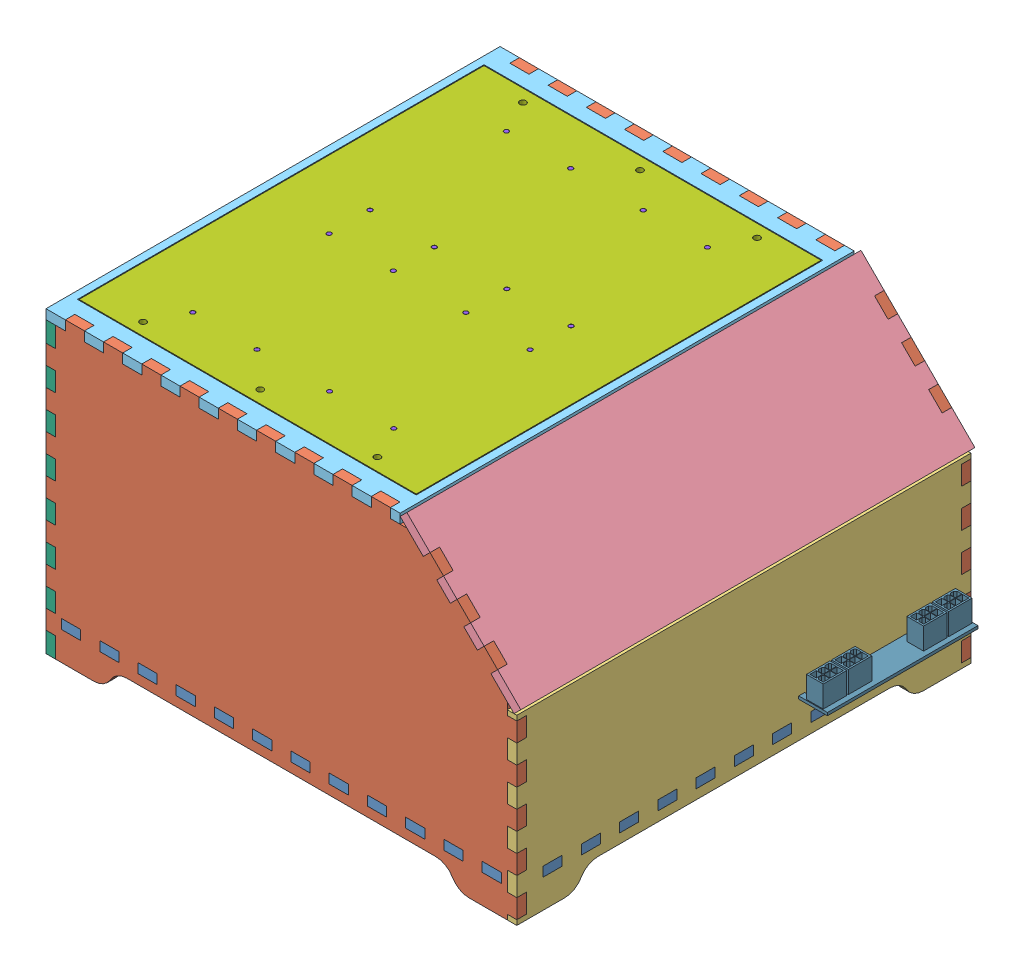
SolidWorks assembly REV 3 Full Machine, configuration Default. Lengths in mm.
Overall size (302.36 180.94 271.43).
34 component instances, 14 part files, 36 mates.
Components (placement in the parent):
- Bottom-1: Bottom [Default] at (-719.689 5.715 -158.5753) x (1 0 0) z (0 -1 0) size (281.43 271.43 5.71)
- Side-1: Side [Default] at (-151.1127 -40.0054 -135.7151) size (281.43 178.58 5.71)
- Side-2: Side [Default] at (-151.1148 -40.0054 130.0001) size (281.43 178.58 5.71)
- Front-1: Front [Default] at (140.7172 -880.4091 158.5753) x (0 1 0) z (-1 0 0) size (108.82 271.43 5.71)
- Front Panel-1: Front Panel [Default] at (-614.3853 853.1825 -158.5753) x (0.707107 -0.707107 0) z (-0.707107 -0.707107 0) size (96.28 271.43 5.71)
- Top-1: Top [Default] at (1145.0391 161.4301 158.5753) x (-1 0 0) z (0 -1 0) size (211.67 271.43 5.71)
- Back-1: Back [Default] at (-140.7152 1444.3252 158.5753) x (0 -1 0) z (1 0 0) size (172.86 271.43 5.71)
- Peltier Assembly 2.0-1: Peltier Assembly 2.0 [Default] at (-34.8782 161.4301 0) x (-1 0 0) z (0 0 1) size (201.5 67.45 242)
  - Cold plate 2.0-1: Cold plate 2.0 [Default] at (-100.75 0 -221.75) x (0 0 1) z (0 1 0) size (242 201.5 3)
  - 91772A162_Passivated 18-8 Stainless Steel Pan Head Phillips Screw-1: 91772A162_Passivated 18-8 Stainless Steel Pan Head Phillips Screw [91772A162] at (21.675 0 93.75) x (0.999996 0 0.002747) z (0 1 0) size (6.86 6.86 16.79)
  - 91772A162_Passivated 18-8 Stainless Steel Pan Head Phillips Screw-2: 91772A162_Passivated 18-8 Stainless Steel Pan Head Phillips Screw [91772A162] at (-21.675 0 93.75) x (0.999996 0 0.002747) z (0 1 0) size (6.86 6.86 16.79)
  - 91772A162_Passivated 18-8 Stainless Steel Pan Head Phillips Screw-3: 91772A162_Passivated 18-8 Stainless Steel Pan Head Phillips Screw [91772A162] at (-60.075 0 93.75) x (0.999996 0 0.002747) z (0 1 0) size (6.86 6.86 16.79)
  - 91772A162_Passivated 18-8 Stainless Steel Pan Head Phillips Screw-4: 91772A162_Passivated 18-8 Stainless Steel Pan Head Phillips Screw [91772A162] at (60.075 0 93.75) x (0.999996 0 0.002747) z (0 1 0) size (6.86 6.86 16.79)
  - 91772A162_Passivated 18-8 Stainless Steel Pan Head Phillips Screw-5: 91772A162_Passivated 18-8 Stainless Steel Pan Head Phillips Screw [91772A162] at (21.675 0 12.25) x (0.999996 0 0.002747) z (0 1 0) size (6.86 6.86 16.79)
  - 91772A162_Passivated 18-8 Stainless Steel Pan Head Phillips Screw-6: 91772A162_Passivated 18-8 Stainless Steel Pan Head Phillips Screw [91772A162] at (-21.675 0 12.25) x (0.999996 0 0.002747) z (0 1 0) size (6.86 6.86 16.79)
  - 91772A162_Passivated 18-8 Stainless Steel Pan Head Phillips Screw-7: 91772A162_Passivated 18-8 Stainless Steel Pan Head Phillips Screw [91772A162] at (-60.075 0 12.25) x (0.999996 0 0.002747) z (0 1 0) size (6.86 6.86 16.79)
  - 91772A162_Passivated 18-8 Stainless Steel Pan Head Phillips Screw-8: 91772A162_Passivated 18-8 Stainless Steel Pan Head Phillips Screw [91772A162] at (21.675 0 -12.25) x (0.999996 0 0.002747) z (0 1 0) size (6.86 6.86 16.79)
  - 91772A162_Passivated 18-8 Stainless Steel Pan Head Phillips Screw-9: 91772A162_Passivated 18-8 Stainless Steel Pan Head Phillips Screw [91772A162] at (60.075 0 12.25) x (0.999996 0 0.002747) z (0 1 0) size (6.86 6.86 16.79)
  - 91772A162_Passivated 18-8 Stainless Steel Pan Head Phillips Screw-10: 91772A162_Passivated 18-8 Stainless Steel Pan Head Phillips Screw [91772A162] at (-21.675 0 -12.25) x (0.946183 0 -0.323632) z (0 1 0) size (6.86 6.86 16.79)
  - 91772A162_Passivated 18-8 Stainless Steel Pan Head Phillips Screw-11: 91772A162_Passivated 18-8 Stainless Steel Pan Head Phillips Screw [91772A162] at (60.075 0 -12.25) x (0.999996 0 0.002747) z (0 1 0) size (6.86 6.86 16.79)
  - 91772A162_Passivated 18-8 Stainless Steel Pan Head Phillips Screw-12: 91772A162_Passivated 18-8 Stainless Steel Pan Head Phillips Screw [91772A162] at (-60.075 0 -12.25) x (0.968243 0 -0.250012) z (0 1 0) size (6.86 6.86 16.79)
  - 91772A162_Passivated 18-8 Stainless Steel Pan Head Phillips Screw-13: 91772A162_Passivated 18-8 Stainless Steel Pan Head Phillips Screw [91772A162] at (60.075 0 -93.75) x (0.999996 0 0.002747) z (0 1 0) size (6.86 6.86 16.79)
  - 91772A162_Passivated 18-8 Stainless Steel Pan Head Phillips Screw-14: 91772A162_Passivated 18-8 Stainless Steel Pan Head Phillips Screw [91772A162] at (21.675 0 -93.75) x (0.999996 0 0.002747) z (0 1 0) size (6.86 6.86 16.79)
  - 91772A162_Passivated 18-8 Stainless Steel Pan Head Phillips Screw-15: 91772A162_Passivated 18-8 Stainless Steel Pan Head Phillips Screw [91772A162] at (-21.675 0 -93.75) x (0.893935 0 0.448197) z (0 1 0) size (6.86 6.86 16.79)
  - 91772A162_Passivated 18-8 Stainless Steel Pan Head Phillips Screw-16: 91772A162_Passivated 18-8 Stainless Steel Pan Head Phillips Screw [91772A162] at (-60.075 0 -93.75) x (-0.993494 0 -0.113885) z (0 1 0) size (6.86 6.86 16.79)
  - Acrylic seperator-1: Acrylic seperator [Default] at (100.75 3 219) x (0 0 -1) z (0 1 0) size (240 200 3)
  - Heatsink 3.0-5: Heatsink 3.0 [Default] at (40.875 6 -53) size (78.2 61.32 89)
  - Heatsink 3.0-6: Heatsink 3.0 [Default] at (-40.875 6 -53) size (78.2 61.32 89)
  - Heatsink 3.0-7: Heatsink 3.0 [Default] at (40.875 6 53) size (78.2 61.32 89)
  - Heatsink 3.0-8: Heatsink 3.0 [Default] at (-40.875 6 53) size (78.2 61.32 89)
- Front Divider-1: Front Divider [Default] at (50.9968 5.715 129.9999) x (0 0 -1) z (0 -1 0) size (260 5.71 150)
- Lower divider-1: Lower divider [Default] at (50.9968 45.715 129.9999) x (0 0 -1) z (1 0 0) size (260 3.05 186)
- PSU-1: PSU [Default] at (-140.7152 11.43 -120.1408) x (0 0 1) z (-1 0 0) size (87 40 208.61)
- PSU adapter board-1: PSU adapter board [Default] at (111.8948 15.75 -77.7658) x (0 0 -1) z (1 0 0) size (90 17.46 103.75)
Mates (geometry in assembly coordinates):
- Symmetric1: symmetric aligned: plane of Bottom-1 through (-5.7154 0 135.7151) normal (0 0 1); plane of Bottom-1 through (-17.1425 0 -135.7151) normal (0 0 -1)
- Symmetric2: symmetric aligned: plane of Bottom-1 through (-140.7155 0 -17.1451) normal (-1 0 0); plane of Bottom-1 through (140.7155 0 -28.5751) normal (1 0 0)
- Coincident5: coincident anti-aligned: plane of Bottom-1 through (-719.689 0 -158.5753) normal (0 -1 0)
- Coincident6: coincident anti-aligned: plane of Bottom-1 through (-120.0155 0 -130.0001) normal (0 0 -1); plane of Side-1 through (-151.1127 -40.0054 -130.0001) normal (0 0 1)
- Coincident7: coincident anti-aligned: plane of Bottom-1 through (-719.689 0 -158.5753) normal (0 -1 0); plane of Side-1 through (-125.7277 0 -130.0001) normal (0 1 0)
- Coincident8: coincident anti-aligned: plane of Bottom-1 through (-131.4427 0 -130.0001) normal (-1 0 0); plane of Side-1 through (-131.4427 0 -130.0001) normal (1 0 0)
- Coincident9: coincident anti-aligned: plane of Bottom-1 through (120.0155 0 135.7151) normal (-1 0 0); plane of Side-2 through (120.0155 0 135.7151) normal (1 0 0)
- Coincident10: coincident anti-aligned: plane of Bottom-1 through (-719.689 0 -158.5753) normal (0 -1 0); plane of Side-2 through (125.7301 0 135.7151) normal (0 1 0)
- Coincident11: coincident aligned: plane of Bottom-1 through (108.5848 0 135.7151) normal (0 0 1); plane of Side-2 through (-151.1148 -40.0054 135.7151) normal (0 0 1)
- Coincident13: coincident anti-aligned: plane of Bottom-1 through (-135.0002 0 40.0049) normal (-1 0 0); plane of Back-1 through (-135.0002 1444.3252 158.5753) normal (1 0 0)
- Coincident14: coincident aligned: plane of Side-1 through (-106.3135 155.7151 -130.0001) normal (0 1 0); plane of Back-1 through (-135.0002 155.7151 -130.0001) normal (0 1 0)
- Coincident15: coincident aligned: plane of Side-2 through (-151.1148 -40.0054 135.7151) normal (0 0 1); plane of Back-1 through (-135.0002 155.7151 135.7151) normal (0 0 1)
- Coincident19: coincident anti-aligned: plane of Top-1 through (1145.0391 155.7151 158.5753) normal (0 -1 0); plane of Back-1 through (-135.0002 155.7151 -130.0001) normal (0 1 0)
- Coincident20: coincident aligned: plane of Top-1 through (-140.7152 155.7151 -130.0001) normal (-1 0 0); plane of Back-1 through (-140.7152 1444.3252 158.5753) normal (-1 0 0)
- Coincident21: coincident aligned: plane of Side-2 through (-151.1148 -40.0054 135.7151) normal (0 0 1); plane of Top-1 through (-106.3167 155.7151 135.7151) normal (0 0 1)
- Coincident22: coincident anti-aligned: plane of Side-1 through (135.0022 20.1189 -130.0001) normal (1 0 0); plane of Front-1 through (135.0022 -880.4091 158.5753) normal (-1 0 0)
- Coincident23: coincident aligned: plane of Side-1 through (112.1426 -17.1452 -130.0001) normal (0 -1 0); plane of Front-1 through (135.0022 -17.1452 -130.0001) normal (0 -1 0)
- Coincident24: coincident anti-aligned: plane of Side-1 through (-151.1127 -40.0054 -130.0001) normal (0 0 1); plane of Front-1 through (135.0022 -2.7416 -130.0001) normal (0 0 -1)
- Coincident25: coincident anti-aligned: plane of Side-2 through (84.7943 145.921 135.7151) normal (0.707107 0.707107 0); plane of Front Panel-1 through (-618.4264 849.1414 -158.5753) normal (-0.707107 -0.707107 0)
- Parallel1: parallel anti-aligned: line of Front-1 through (135.0022 91.6735 135.7151) axis (0 0 -1); line of Front Panel-1 through (139.0411 91.6738 -135.7151) axis (0 0 1)
- Coincident27: coincident aligned: plane of Side-2 through (-151.1148 -40.0054 135.7151) normal (0 0 1); plane of Front Panel-1 through (100.96 129.7549 135.7151) normal (0 0 1)
- Coincident28: coincident: point of Side-2; unknown of Front Panel-1
- Coincident29: coincident aligned: plane of Top-1 through (1145.0391 161.4301 158.5753) normal (0 1 0); plane of Peltier Assembly 2.0-1/Cold plate 2.0-1 through (-34.8782 161.4301 0) normal (0 1 0)
- Width1: width anti-aligned: plane of Peltier Assembly 2.0-1/Cold plate 2.0-1 through (65.8718 158.4301 -121) normal (1 0 0); plane of Top-1 through (-135.6282 158.4301 -121) normal (-1 0 0); plane of Peltier Assembly 2.0-1/Cold plate 2.0-1 through (-140.7152 155.7151 -130.0001) normal (-1 0 0); plane of Top-1 through (70.9587 155.7151 -130.0001) normal (1 0 0)
- Width2: width anti-aligned: plane of Peltier Assembly 2.0-1/Cold plate 2.0-1 through (-135.6282 158.4301 121) normal (0 0 1); plane of Side-1 through (-135.6282 158.4301 -121) normal (0 0 -1); plane of Peltier Assembly 2.0-1/Cold plate 2.0-1 through (-151.1127 -40.0054 -135.7151) normal (0 0 -1); plane of Side-2 through (-151.1148 -40.0054 135.7151) normal (0 0 1)
- Coincident30: coincident anti-aligned: plane of Side-1 through (-151.1127 -40.0054 -130.0001) normal (0 0 1); plane of Front Divider-1 through (56.7118 5.715 -130.0001) normal (0 0 -1)
- Coincident31: coincident anti-aligned: plane of Bottom-1 through (-719.689 5.715 -158.5753) normal (0 1 0); plane of Front Divider-1 through (56.7118 5.715 129.9999) normal (0 -1 0)
- Distance1: distance = 1 mm anti-aligned: plane of Front Divider-1 through (50.9968 5.715 129.9999) normal (-1 0 0); plane of Peltier Assembly 2.0-1/Heatsink 2.0-3 through (49.9968 122.5801 52.5) normal (1 0 0)
- Coincident33: coincident anti-aligned: plane of Front Divider-1 through (50.9968 5.715 129.9999) normal (-1 0 0); plane of Lower divider-1 through (50.9968 48.763 129.9999) normal (1 0 0)
- Coincident34: coincident aligned: plane of Front Divider-1 through (56.7118 5.715 129.9999) normal (0 0 1); plane of Lower divider-1 through (50.9968 48.763 129.9999) normal (0 0 1)
- Distance2: distance = 40 mm anti-aligned: plane of Bottom-1 through (-719.689 5.715 -158.5753) normal (0 1 0); plane of Lower divider-1 through (50.9968 45.715 129.9999) normal (0 -1 0)
- Coincident36: coincident aligned: plane of Back-1 through (-140.7152 1444.3252 158.5753) normal (-1 0 0); plane of PSU-1 through (-140.7152 6.215 -120.1408) normal (-1 0 0)
- Distance3: distance = 5.715 mm anti-aligned: plane of PSU-1 through (-106.7152 11.43 -120.1408) normal (0 -1 0); plane of Bottom-1 through (-719.689 5.715 -158.5753) normal (0 1 0)
- Coincident37: coincident anti-aligned: plane of PSU-1 through (64.1448 6.215 -120.1408) normal (1 0 0); plane of PSU adapter board-1 through (64.1448 10.535 -77.7658) normal (-1 0 0)
- Width3: width aligned: plane of PSU adapter board-1 through (64.1448 12.59 -45.2658) normal (0 0 -1); plane of PSU adapter board-1 through (64.1448 12.59 -110.2658) normal (0 0 1); plane of PSU-1 through (64.1448 12.215 -110.3908) normal (0 0 -1); plane of PSU-1 through (64.1448 12.215 -45.1408) normal (0 0 1)
- Width4: width anti-aligned: plane of PSU adapter board-1 through (64.1448 10.19 -110.2658) normal (0 1 0); plane of PSU adapter board-1 through (64.1448 12.59 -110.2658) normal (0 -1 0); plane of PSU-1 through (64.1448 10.565 -45.1408) normal (0 -1 0); plane of PSU-1 through (64.1448 12.215 -45.1408) normal (0 1 0)
